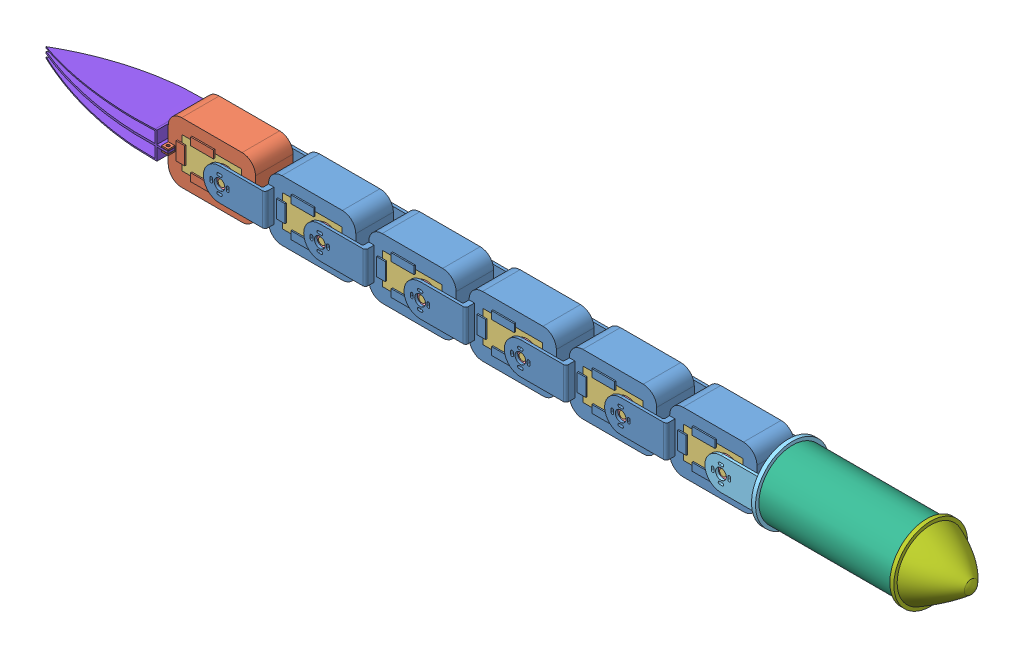
SolidWorks assembly bus_assembly, configuration 預設. Lengths in mm.
Overall size (691.28 55 55).
28 component instances, 8 part files, 89 mates.
Components (placement in the parent):
- bus2-1: bus2 [預設] at (12.4546 -2.1213 92.75) size (107 45 40.5)
- bus2-2: bus2 [預設] at (-62.2454 -2.1213 92.75) size (107 45 40.5)
- bus2-3: bus2 [預設] at (-286.3454 -2.1213 92.75) size (107 45 40.5)
- bus2-4: bus2 [預設] at (-136.9454 -2.1213 92.75) size (107 45 40.5)
- bus2-5: bus2 [預設] at (-211.6454 -2.1213 92.75) size (107 45 40.5)
- bus2_tail-1: bus2_tail [預設] at (-361.0454 -2.1213 92.75) size (65 45 38)
- bus_servo-1: bus_servo [預設] at (-368.5322 -13.6144 92.75) x (1 0 0) z (0 -1 0) size (44.4 38 23.4)
- bus_servo_cicrcle1-1: bus_servo_cicrcle1 [預設] at (-376.28 -2.2213 122.25) size (20 20 3)
- bus_servo_cicrcle1-2: bus_servo_cicrcle1 [預設] at (-376.28 -2.1213 88.75) size (20 20 3)
- bus_servo-2: bus_servo [預設] at (-293.8322 -13.6144 92.75) x (1 0 0) z (0 -1 0) size (44.4 38 23.4)
- bus_servo-3: bus_servo [預設] at (-219.1322 -13.6144 92.75) x (1 0 0) z (0 -1 0) size (44.4 38 23.4)
- bus_servo-4: bus_servo [預設] at (-144.4322 9.3718 120.75) x (1 0 0) z (0 1 0) size (44.4 38 23.4)
- bus_servo-5: bus_servo [預設] at (-69.7322 -13.6144 92.75) x (1 0 0) z (0 -1 0) size (44.4 38 23.4)
- bus_servo-6: bus_servo [預設] at (4.9678 -13.6144 92.75) x (1 0 0) z (0 -1 0) size (44.4 38 23.4)
- bus_servo_cicrcle1-3: bus_servo_cicrcle1 [預設] at (-301.58 -2.1213 122.25) size (20 20 3)
- bus_servo_cicrcle1-4: bus_servo_cicrcle1 [預設] at (-301.58 -2.1213 88.75) size (20 20 3)
- bus_servo_cicrcle1-5: bus_servo_cicrcle1 [預設] at (-226.88 -2.1213 88.75) size (20 20 3)
- bus_servo_cicrcle1-6: bus_servo_cicrcle1 [預設] at (-226.88 -2.1213 122.25) size (20 20 3)
- bus_servo_cicrcle1-7: bus_servo_cicrcle1 [預設] at (-152.18 -2.1213 122.25) size (20 20 3)
- bus_servo_cicrcle1-8: bus_servo_cicrcle1 [預設] at (-152.18 -2.1213 88.75) size (20 20 3)
- bus_servo_cicrcle1-9: bus_servo_cicrcle1 [預設] at (-77.48 -2.1213 122.25) size (20 20 3)
- bus_servo_cicrcle1-10: bus_servo_cicrcle1 [預設] at (-77.48 -2.1213 88.75) size (20 20 3)
- bus_servo_cicrcle1-11: bus_servo_cicrcle1 [預設] at (-2.78 -2.1213 88.75) size (20 20 3)
- bus_servo_cicrcle1-12: bus_servo_cicrcle1 [預設] at (-2.78 -2.1213 122.25) x (0 1 0) z (0 0 1) size (20 20 3)
- bus_lib_tail-1: bus_lib_tail [預設] at (30.22 -2.1213 107) x (0 1 0) z (0 0 -1) size (55 65 55)
- bus_body-1: bus_body [預設] at (30.22 -2.1213 107) x (0 -0.997513 -0.070479) z (0 -0.070479 0.997513) size (50 100 50)
- bus_lib_head_1-1: bus_lib_head_1 [預設] at (130.22 -2.1213 107) x (0 1 0) z (0 0 1) size (55 54.98 55)
- bus_final_tail-2: bus_final_tail [預設] at (-425.0707 -2.1213 107.4806) x (-1 0 -0.00071) z (0 -1 0) size (110.1 38.13 25.31)
Mates (geometry in assembly coordinates):
- 重合/共線/共點1: coincident: plane of bus2-1 through (12.4546 -2.1213 120.75) normal (0 0 1); plane of bus2-2 through (-62.2454 -2.1213 120.75) normal (0 0 1)
- 重合/共線/共點2: coincident: plane of bus2-1 through (-47.48 20.3787 120.75) normal (0 1 0); plane of bus2-2 through (-122.18 20.3787 120.75) normal (0 1 0)
- 重合/共線/共點3: coincident: plane of bus2-3 through (-286.3454 -2.1213 120.75) normal (0 0 1); plane of bus2-2 through (-62.2454 -2.1213 120.75) normal (0 0 1)
- 重合/共線/共點4: coincident: plane of bus2-2 through (-122.18 20.3787 120.75) normal (0 1 0); plane of bus2-3 through (-346.28 20.3787 120.75) normal (0 1 0)
- 重合/共線/共點5: coincident: plane of bus2-3 through (-346.28 20.3787 120.75) normal (0 1 0); plane of bus2-4 through (-196.88 20.3787 120.75) normal (0 1 0)
- 重合/共線/共點6: coincident: plane of bus2-3 through (-286.3454 -2.1213 120.75) normal (0 0 1); plane of bus2-4 through (-136.9454 -2.1213 120.75) normal (0 0 1)
- 重合/共線/共點9: coincident: plane of bus2-3 through (-346.28 20.3787 120.75) normal (0 1 0); plane of bus2-5 through (-271.58 20.3787 120.75) normal (0 1 0)
- 重合/共線/共點10: coincident: plane of bus2-3 through (-286.3454 -2.1213 120.75) normal (0 0 1); plane of bus2-5 through (-211.6454 -2.1213 120.75) normal (0 0 1)
- 重合/共線/共點11: coincident: plane of bus2-3 through (-286.3454 -2.1213 120.75) normal (0 0 1); plane of bus2_tail-1 through (-361.0454 -2.1213 120.75) normal (0 0 1)
- 重合/共線/共點12: coincident: plane of bus2-3 through (-346.28 20.3787 120.75) normal (0 1 0); plane of bus2_tail-1 through (-420.98 20.3787 120.75) normal (0 1 0)
- 同軸心1: concentric: cylinder of bus2_tail-1 through (-418.48 2.8787 123.25) axis (0 -1 0) radius 1.1; cylinder of ? through (-418.48 -1.3713 123.25) axis (0 -1 0) radius 1.1
- 同軸心2: concentric: cylinder of bus2_tail-1 through (-418.48 2.8787 90.25) axis (0 -1 0) radius 1.1; cylinder of ? through (-418.48 -1.3713 90.25) axis (0 -1 0) radius 1.1
- 平行相距1: distance = 0.25 mm: line of ? through (-415.9818 -1.3713 125.7518) axis (-1 0 -0.00071); line of bus2_tail-1 through (-420.98 -1.1213 125.75) axis (1 0 0)
- 重合/共線/共點13: coincident: plane of bus2_tail-1 through (-410.68 -13.8213 131.75) normal (0 1 0); plane of bus_servo-1 through (-410.68 -13.8213 120.75) normal (0 -1 0)
- 重合/共線/共點14: coincident: plane of bus2_tail-1 through (-366.28 9.5787 131.75) normal (-1 0 0); plane of bus_servo-1 through (-366.28 9.5787 120.75) normal (1 0 0)
- 重合/共線/共點17: coincident: plane of bus2_tail-1 through (-361.0454 -2.1213 120.75) normal (0 0 1); plane of bus_servo-1 through (-368.5322 -13.6144 120.75) normal (0 0 1)
- 重合/共線/共點18: coincident: plane of bus2-3 through (-377.33 2.9787 86.75) normal (0 1 0); plane of bus_servo_cicrcle1-1 through (-377.33 2.9787 126.25) normal (0 1 0)
- 平行2: parallel: plane of bus2-3 through (-377.33 -9.3213 86.75) normal (0 1 0); plane of bus_servo_cicrcle1-1 through (-377.33 -9.4213 126.25) normal (0 1 0)
- 重合/共線/共點21: coincident: plane of bus2-3 through (-383.48 -1.0713 86.75) normal (1 0 0); plane of bus_servo_cicrcle1-1 through (-383.48 -1.1713 126.25) normal (1 0 0)
- 平行3: parallel: cylinder of bus2-3 through (-376.28 -2.1213 125.25) axis (0 0 1) radius 4; cylinder of bus_servo_cicrcle1-1 through (-376.28 -2.2213 126.25) axis (0 0 -1) radius 4
- 重合/共線/共點22: coincident: plane of bus2-3 through (-376.28 -2.1213 125.25) normal (0 0 -1); plane of bus_servo_cicrcle1-1 through (-376.28 -2.2213 125.25) normal (0 0 1)
- 重合/共線/共點23: coincident: plane of bus2-3 through (-376.28 -2.1213 88.75) normal (0 0 1); plane of bus_servo_cicrcle1-2 through (-376.28 -2.1213 88.75) normal (0 0 -1)
- 同軸心5: concentric: cylinder of bus2-3 through (-376.28 -2.1213 86.75) axis (0 0 1) radius 3.7; cylinder of bus_servo_cicrcle1-2 through (-376.28 -2.1213 92.75) axis (0 0 -1) radius 4
- 同軸心8: concentric: cylinder of bus2-3 through (-376.28 -2.1213 86.75) axis (0 0 1) radius 3.7; cylinder of bus_servo-1 through (-376.28 -2.1213 87.75) axis (0 0 1) radius 2.5
- 重合/共線/共點24: coincident: plane of bus2-3 through (-335.98 -13.8213 131.75) normal (0 1 0); plane of bus_servo-2 through (-335.98 -13.8213 120.75) normal (0 -1 0)
- 重合/共線/共點25: coincident: plane of bus2-3 through (-335.98 9.5787 131.75) normal (1 0 0); plane of bus_servo-2 through (-335.98 9.5787 120.75) normal (-1 0 0)
- 重合/共線/共點26: coincident: plane of bus2-3 through (-286.3454 -2.1213 92.75) normal (0 0 -1); plane of bus_servo-2 through (-293.8322 -13.6144 92.75) normal (0 0 -1)
- 重合/共線/共點27: coincident: plane of bus2-5 through (-261.28 -13.8213 131.75) normal (0 1 0); plane of bus_servo-3 through (-261.28 -13.8213 120.75) normal (0 -1 0)
- 重合/共線/共點28: coincident: plane of bus2-5 through (-261.28 9.5787 131.75) normal (1 0 0); plane of bus_servo-3 through (-261.28 9.5787 120.75) normal (-1 0 0)
- 重合/共線/共點29: coincident: plane of bus2-5 through (-211.6454 -2.1213 92.75) normal (0 0 -1); plane of bus_servo-3 through (-219.1322 -13.6144 92.75) normal (0 0 -1)
- 重合/共線/共點30: coincident: plane of bus2-2 through (-111.88 9.5787 131.75) normal (0 -1 0); plane of bus_servo-4 through (-186.58 9.5787 92.75) normal (0 1 0)
- 重合/共線/共點31: coincident: plane of bus2-4 through (-142.18 9.5787 131.75) normal (-1 0 0); plane of bus_servo-4 through (-142.18 -13.8213 92.75) normal (1 0 0)
- 重合/共線/共點32: coincident: plane of bus2-4 through (-136.9454 -2.1213 120.75) normal (0 0 1); plane of bus_servo-4 through (-144.4322 9.3718 120.75) normal (0 0 1)
- 重合/共線/共點37: coincident: plane of bus2-2 through (-111.88 9.5787 131.75) normal (0 -1 0); plane of bus_servo-5 through (-111.88 9.5787 120.75) normal (0 1 0)
- 重合/共線/共點38: coincident: plane of bus2-2 through (-67.48 9.5787 131.75) normal (-1 0 0); plane of bus_servo-5 through (-67.48 9.5787 120.75) normal (1 0 0)
- 重合/共線/共點40: coincident: plane of bus2-2 through (-62.2454 -2.1213 120.75) normal (0 0 1); plane of bus_servo-5 through (-69.7322 -13.6144 120.75) normal (0 0 1)
- 重合/共線/共點42: coincident: plane of bus2-1 through (12.4546 -2.1213 120.75) normal (0 0 1); plane of bus_servo-6 through (4.9678 -13.6144 120.75) normal (0 0 1)
- 重合/共線/共點43: coincident: plane of bus2-1 through (-37.18 9.5787 131.75) normal (1 0 0); plane of bus_servo-6 through (-37.18 9.5787 120.75) normal (-1 0 0)
- 重合/共線/共點44: coincident: plane of bus2-1 through (-37.18 9.5787 131.75) normal (0 -1 0); plane of bus_servo-6 through (-37.18 9.5787 120.75) normal (0 1 0)
- 同軸心9: concentric: cylinder of bus2-5 through (-301.58 -2.1213 125.25) axis (0 0 1) radius 4; cylinder of bus_servo_cicrcle1-3 through (-301.58 -2.1213 126.25) axis (0 0 -1) radius 4
- 重合/共線/共點45: coincident: plane of bus2-5 through (-301.58 -2.1213 125.25) normal (0 0 -1); plane of bus_servo_cicrcle1-3 through (-301.58 -2.1213 125.25) normal (0 0 1)
- 同軸心10: concentric: cylinder of bus2-5 through (-301.58 -2.1213 86.75) axis (0 0 1) radius 3.7; cylinder of bus_servo_cicrcle1-4 through (-301.58 -2.1213 92.75) axis (0 0 -1) radius 4
- 重合/共線/共點46: coincident: plane of bus2-5 through (-301.58 -2.1213 88.75) normal (0 0 1); plane of bus_servo_cicrcle1-4 through (-301.58 -2.1213 88.75) normal (0 0 -1)
- 同軸心11: concentric: cylinder of bus2-4 through (-226.88 -2.1213 125.25) axis (0 0 1) radius 4; cylinder of bus_servo_cicrcle1-6 through (-226.88 -2.1213 126.25) axis (0 0 -1) radius 4
- 重合/共線/共點47: coincident: plane of bus2-4 through (-226.88 -2.1213 125.25) normal (0 0 -1); plane of bus_servo_cicrcle1-6 through (-226.88 -2.1213 125.25) normal (0 0 1)
- 同軸心12: concentric: cylinder of bus2-4 through (-226.88 -2.1213 86.75) axis (0 0 1) radius 3.7; cylinder of bus_servo_cicrcle1-5 through (-226.88 -2.1213 92.75) axis (0 0 -1) radius 4
- 重合/共線/共點48: coincident: plane of bus2-4 through (-226.88 -2.1213 88.75) normal (0 0 1); plane of bus_servo_cicrcle1-5 through (-226.88 -2.1213 88.75) normal (0 0 -1)
- 同軸心13: concentric: cylinder of bus2-2 through (-152.18 -2.1213 86.75) axis (0 0 1) radius 3.7; cylinder of bus_servo_cicrcle1-8 through (-152.18 -2.1213 92.75) axis (0 0 -1) radius 4
- 重合/共線/共點49: coincident: plane of bus2-2 through (-152.18 -2.1213 88.75) normal (0 0 1); plane of bus_servo_cicrcle1-8 through (-152.18 -2.1213 88.75) normal (0 0 -1)
- 同軸心14: concentric: cylinder of bus2-2 through (-152.18 -2.1213 125.25) axis (0 0 1) radius 4; cylinder of bus_servo_cicrcle1-7 through (-152.18 -2.1213 126.25) axis (0 0 -1) radius 4
- 重合/共線/共點51: coincident: plane of bus2-2 through (-152.18 -2.1213 125.25) normal (0 0 -1); plane of bus_servo_cicrcle1-7 through (-152.18 -2.1213 125.25) normal (0 0 1)
- 重合/共線/共點52: coincident: plane of bus2-5 through (-302.63 -9.3213 125.25) normal (0 1 0); plane of bus_servo_cicrcle1-3 through (-302.63 -9.3213 126.25) normal (0 1 0)
- 平行6: parallel: plane of bus2-5 through (-294.48 -1.0713 125.25) normal (-1 0 0); plane of bus_servo_cicrcle1-3 through (-294.38 -1.0713 126.25) normal (-1 0 0)
- 平行8: parallel: plane of bus2-4 through (-219.78 -1.0713 125.25) normal (-1 0 0); plane of bus_servo_cicrcle1-6 through (-219.68 -1.0713 126.25) normal (-1 0 0)
- 重合/共線/共點56: coincident: plane of bus2-4 through (-227.93 -9.3213 125.25) normal (0 1 0); plane of bus_servo_cicrcle1-6 through (-227.93 -9.3213 126.25) normal (0 1 0)
- 平行9: parallel: plane of bus2-4 through (-219.78 -1.0713 86.75) normal (-1 0 0); plane of bus_servo_cicrcle1-5 through (-219.68 -1.0713 92.75) normal (-1 0 0)
- 平行10: parallel: plane of bus2-4 through (-227.93 4.9787 86.75) normal (0 -1 0); plane of bus_servo_cicrcle1-5 through (-227.93 5.0787 92.75) normal (0 -1 0)
- 平行11: parallel: line of bus2-2 through (-153.23 2.9787 127.25) axis (1 0 0); plane of bus_servo_cicrcle1-7 through (-153.23 3.0787 126.25) normal (0 1 0)
- 平行12: parallel: plane of bus2-2 through (-145.08 -1.0713 125.25) normal (-1 0 0); plane of bus_servo_cicrcle1-7 through (-144.98 -1.0713 126.25) normal (-1 0 0)
- 重合/共線/共點61: coincident: plane of bus2-2 through (-153.23 -7.3213 86.75) normal (0 -1 0); plane of bus_servo_cicrcle1-8 through (-153.23 -7.3213 92.75) normal (0 -1 0)
- 平行13: parallel: plane of bus2-2 through (-145.08 -1.0713 86.75) normal (-1 0 0); plane of bus_servo_cicrcle1-8 through (-144.98 -1.0713 92.75) normal (-1 0 0)
- 重合/共線/共點63: coincident: plane of bus2-1 through (-77.48 -2.1213 88.75) normal (0 0 1); plane of bus_servo_cicrcle1-10 through (-77.48 -2.1213 88.75) normal (0 0 -1)
- 同軸心15: concentric: cylinder of bus2-1 through (-77.48 -2.1213 86.75) axis (0 0 1) radius 3.7; cylinder of bus_servo_cicrcle1-10 through (-77.48 -2.1213 92.75) axis (0 0 -1) radius 4
- 平行14: parallel: plane of bus2-1 through (-78.53 2.9787 86.75) normal (0 1 0); plane of bus_servo_cicrcle1-10 through (-78.53 3.0787 92.75) normal (0 1 0)
- 同軸心16: concentric: cylinder of bus2-1 through (-77.48 -2.1213 125.25) axis (0 0 1) radius 4; cylinder of bus_servo_cicrcle1-9 through (-77.48 -2.1213 126.25) axis (0 0 -1) radius 4
- 重合/共線/共點65: coincident: plane of bus2-1 through (-77.48 -2.1213 125.25) normal (0 0 -1); plane of bus_servo_cicrcle1-9 through (-77.48 -2.1213 125.25) normal (0 0 1)
- 平行15: parallel: plane of bus2-1 through (-78.53 2.9787 125.25) normal (0 1 0); plane of bus_servo_cicrcle1-9 through (-78.53 3.0787 126.25) normal (0 1 0)
- 同軸心17: concentric: cylinder of bus_servo-2 through (-301.58 -2.1213 120.75) axis (0 0 1) radius 2.5; cylinder of bus_servo_cicrcle1-3 through (-301.58 -2.1213 126.25) axis (0 0 -1) radius 4
- 同軸心18: concentric: cylinder of bus_servo-3 through (-226.88 -2.1213 120.75) axis (0 0 1) radius 2.5; cylinder of bus_servo_cicrcle1-6 through (-226.88 -2.1213 126.25) axis (0 0 -1) radius 4
- 同軸心37: concentric: cylinder of bus_servo-4 through (-152.18 -2.1213 125.75) axis (0 0 -1) radius 2.5; cylinder of bus_servo_cicrcle1-7 through (-152.18 -2.1213 126.25) axis (0 0 -1) radius 4
- 同軸心39: concentric: cylinder of bus_servo-5 through (-77.48 -2.1213 87.75) axis (0 0 1) radius 2.5; cylinder of bus_servo_cicrcle1-10 through (-77.48 -2.1213 92.75) axis (0 0 -1) radius 4
- 重合/共線/共點76: coincident: plane of bus_servo_cicrcle1-12 through (-2.78 -2.1213 125.25) normal (0 0 1); plane of bus_lib_tail-1 through (-2.78 -2.1213 125.25) normal (0 0 -1)
- 重合/共線/共點77: coincident: plane of bus_servo_cicrcle1-11 through (-2.78 -2.1213 88.75) normal (0 0 -1); plane of bus_lib_tail-1 through (-2.78 -2.1213 88.75) normal (0 0 1)
- 同軸心41: concentric: cylinder of bus_servo_cicrcle1-11 through (-2.78 -2.1213 92.75) axis (0 0 -1) radius 4; cylinder of bus_lib_tail-1 through (-2.78 -2.1213 88.75) axis (0 0 -1) radius 4
- 重合/共線/共點78: coincident: plane of bus_servo_cicrcle1-11 through (-7.98 -1.0713 92.75) normal (-1 0 0); plane of bus_lib_tail-1 through (-7.98 -3.1713 88.75) normal (-1 0 0)
- 重合/共線/共點79: coincident: plane of bus_servo_cicrcle1-11 through (-3.83 -9.3213 92.75) normal (0 1 0); plane of bus_lib_tail-1 through (-1.73 -9.3213 88.75) normal (0 1 0)
- 重合/共線/共點80: coincident: plane of bus_servo_cicrcle1-12 through (-3.83 -9.3213 126.25) normal (0 1 0); plane of bus_lib_tail-1 through (-1.73 -9.3213 127.25) normal (0 1 0)
- 重合/共線/共點81: coincident: plane of bus_servo_cicrcle1-12 through (4.42 -3.1713 126.25) normal (-1 0 0); plane of bus_lib_tail-1 through (4.42 -3.1713 127.25) normal (-1 0 0)
- 同軸心42: concentric: cylinder of bus_servo_cicrcle1-12 through (-2.78 -2.1213 126.25) axis (0 0 -1) radius 4; cylinder of bus_lib_tail-1 through (-2.78 -2.1213 127.25) axis (0 0 -1) radius 4
- 同軸心43: concentric: cylinder of bus_servo-6 through (-2.78 -2.1213 120.75) axis (0 0 1) radius 2.5; cylinder of bus_servo_cicrcle1-12 through (-2.78 -2.1213 126.25) axis (0 0 -1) radius 4
- 重合/共線/共點82: coincident: plane of bus2-1 through (-47.48 9.8787 126.75) normal (0 1 0); plane of bus_lib_tail-1 through (27.22 9.8787 127.25) normal (0 1 0)
- 重合/共線/共點83: coincident: plane of bus2-1 through (-77.48 -2.1213 127.25) normal (0 0 1); plane of bus_lib_tail-1 through (-2.78 -2.1213 127.25) normal (0 0 1)
- 同軸心44: concentric: cylinder of bus_lib_tail-1 through (35.22 -2.1213 107) axis (1 0 0) radius 21.75; cylinder of bus_body-1 through (130.22 -2.1213 107) axis (-1 0 0) radius 22
- 重合/共線/共點84: coincident: plane of bus_lib_tail-1 through (30.22 -2.1213 107) normal (1 0 0); plane of bus_body-1 through (30.22 -2.1213 107) normal (-1 0 0)
- 同軸心45: concentric: cylinder of bus_body-1 through (130.22 -2.1213 107) axis (-1 0 0) radius 22; cylinder of bus_lib_head_1-1 through (115.72 -2.1213 107) axis (1 0 0) radius 21.75
- 重合/共線/共點85: coincident: plane of bus_body-1 through (130.22 -2.1213 107) normal (1 0 0); plane of bus_lib_head_1-1 through (130.22 -2.1213 107) normal (-1 0 0)
- 同軸心46: concentric: cylinder of bus2_tail-1 through (-418.48 2.8787 123.25) axis (0 -1 0) radius 1.1; cylinder of bus_final_tail-2 through (-418.48 -1.3713 123.25) axis (0 -1 0) radius 1.1
- 同軸心47: concentric: cylinder of bus2_tail-1 through (-418.48 2.8787 90.25) axis (0 -1 0) radius 1.1; cylinder of bus_final_tail-2 through (-418.48 -1.3713 90.25) axis (0 -1 0) radius 1.1
- 平行相距2: distance = 0.25 mm: plane of bus_final_tail-2 through (-425.0707 -1.3713 107.4806) normal (0 1 0); plane of bus2_tail-1 through (-361.0454 -1.1213 92.75) normal (0 -1 0)
